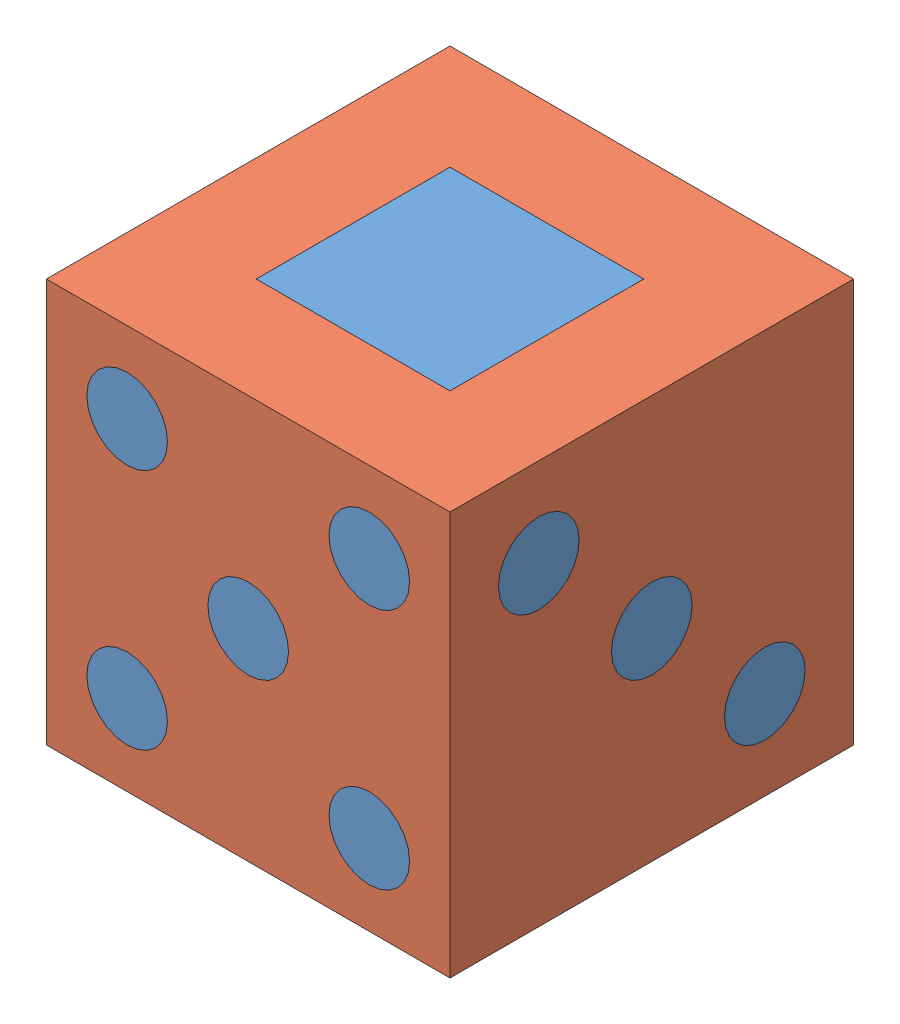
SolidWorks assembly edited, configuration Default. Lengths in mm.
Overall size (25 25 25).
2 component instances, 2 part files, 5 mates.
Components (placement in the parent):
- Inner edited-1: Inner edited [Default] at (1.6314 7.5257 26.7993) size (25 25 25)
- outer edited-2: outer edited [Default] at (1.6314 7.5257 26.7993) size (25 25 25)
Mates (geometry in assembly coordinates):
- Coincident1: coincident anti-aligned: plane of outer edited-1 through (7.6327 17.7163 20.8735) normal (-1 0 0); plane of Inner edited-1 through (7.6314 13.0552 20.7993) normal (1 0 0)
- Coincident2: coincident anti-aligned: plane of outer edited-1 through (-4.3673 17.7163 20.8735) normal (0 0 1); plane of Inner edited-1 through (-4.3686 13.0552 20.7993) normal (0 0 -1)
- Coincident4: coincident aligned: plane of outer edited-1 through (1.6327 32.7163 26.8735) normal (0 1 0); plane of Inner edited-1 through (1.6314 32.5257 26.7993) normal (0 1 0)
- Concentric1: concentric aligned: cylinder of Inner edited-1 through (1.6314 20.0257 29.7282) axis (0 0 1) radius 2.5; cylinder of outer edited-2 through (1.6314 20.0257 24.2993) axis (0 0 1) radius 2.5
- Coincident5: coincident aligned: plane of Inner edited-1 through (1.6314 26.0257 14.2993) normal (0 0 -1); plane of outer edited-2 through (-10.8686 32.5257 14.2993) normal (0 0 -1)
